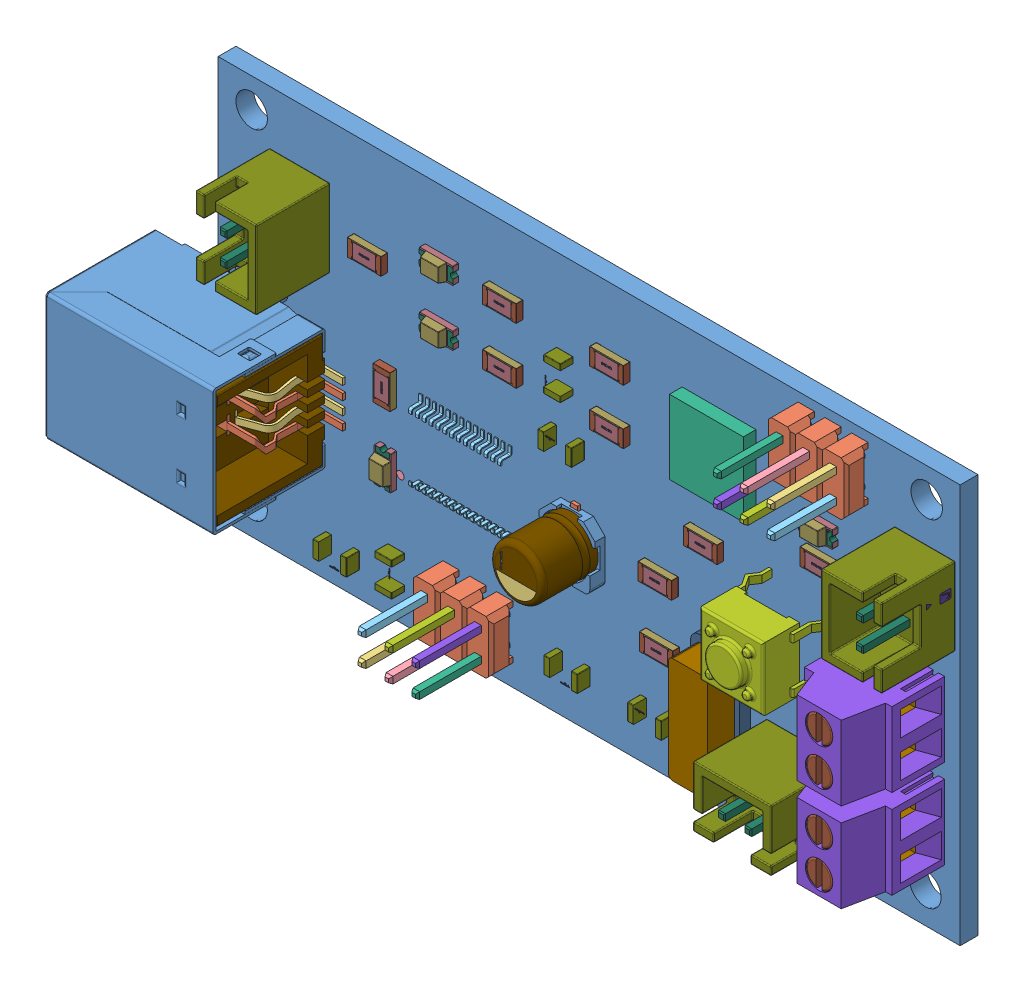
SolidWorks assembly MCU_PCB.step, configuration Default. Lengths in mm.
Overall size (75.68 37.85 14.81).
230 component instances, 41 part files, 0 mates.
Components (placement in the parent):
- Board.step-1: Board.step [Default] at origin size (70.36 37.85 1.69)
  - Open CASCADE STEP translator 7.5 1.1.1.step-1: Open CASCADE STEP translator 7.5 1.1.1.step [Default] at (0 0 -1.6914) size (70.36 37.85 1.69)
- J8.step-1: J8.step [Default] at origin size (7.62 5.08 11.68)
  - Conn_Harwin_M20-9980346_eec.step-1: Conn_Harwin_M20-9980346_eec.step [Default] at (78.623 59.827 2.54) x (1 0 0) z (0 -1 0) size (7.62 2.54 5.08)
  - Conn_Harwin_M20-9980346_eec-0.step-1: Conn_Harwin_M20-9980346_eec-0.step [Default] at (78.623 59.827 2.54) x (1 0 0) z (0 -1 0) size (0.64 11.68 0.63)
  - Conn_Harwin_M20-9980346_eec-1.step-1: Conn_Harwin_M20-9980346_eec-1.step [Default] at (78.623 59.827 2.54) x (1 0 0) z (0 -1 0) size (0.64 11.68 0.63)
  - Conn_Harwin_M20-9980346_eec-2.step-1: Conn_Harwin_M20-9980346_eec-2.step [Default] at (78.623 59.827 2.54) x (1 0 0) z (0 -1 0) size (0.64 11.68 0.63)
  - Conn_Harwin_M20-9980346_eec-3.step-1: Conn_Harwin_M20-9980346_eec-3.step [Default] at (78.623 59.827 2.54) x (1 0 0) z (0 -1 0) size (0.63 11.68 0.63)
  - Conn_Harwin_M20-9980346_eec-4.step-1: Conn_Harwin_M20-9980346_eec-4.step [Default] at (78.623 59.827 2.54) x (1 0 0) z (0 -1 0) size (0.64 11.68 0.63)
  - Conn_Harwin_M20-9980346_eec-5.step-1: Conn_Harwin_M20-9980346_eec-5.step [Default] at (78.623 59.827 2.54) x (1 0 0) z (0 -1 0) size (0.63 11.68 0.63)
- J7.step-1: J7.step [Default] at origin size (7.62 5.08 11.68)
  - Conn_Harwin_M20-9980346_eec.step-1: Conn_Harwin_M20-9980346_eec.step [Default] at (55.108 29.962 2.54) x (-1 0 0) z (0 1 0) size (7.62 2.54 5.08)
  - Conn_Harwin_M20-9980346_eec-0.step-1: Conn_Harwin_M20-9980346_eec-0.step [Default] at (55.108 29.962 2.54) x (-1 0 0) z (0 1 0) size (0.64 11.68 0.63)
  - Conn_Harwin_M20-9980346_eec-1.step-1: Conn_Harwin_M20-9980346_eec-1.step [Default] at (55.108 29.962 2.54) x (-1 0 0) z (0 1 0) size (0.64 11.68 0.63)
  - Conn_Harwin_M20-9980346_eec-2.step-1: Conn_Harwin_M20-9980346_eec-2.step [Default] at (55.108 29.962 2.54) x (-1 0 0) z (0 1 0) size (0.64 11.68 0.63)
  - Conn_Harwin_M20-9980346_eec-3.step-1: Conn_Harwin_M20-9980346_eec-3.step [Default] at (55.108 29.962 2.54) x (-1 0 0) z (0 1 0) size (0.63 11.68 0.63)
  - Conn_Harwin_M20-9980346_eec-4.step-1: Conn_Harwin_M20-9980346_eec-4.step [Default] at (55.108 29.962 2.54) x (-1 0 0) z (0 1 0) size (0.64 11.68 0.63)
  - Conn_Harwin_M20-9980346_eec-5.step-1: Conn_Harwin_M20-9980346_eec-5.step [Default] at (55.108 29.962 2.54) x (-1 0 0) z (0 1 0) size (0.63 11.68 0.63)
- Y1.step-1: Y1.step [Default] at origin size (4.66 11.36 3.61)
  - 6150083568.step-1: 6150083568.step [Default] at (73.5331 33.9361 1) size (3.71 10.05 2.61)
    - Extruded.step-1: Extruded.step [Default] at origin size (3.71 10.05 2.61)
  - 6150083488.step-1: 6150083488.step [Default] at (73.5329 33.9361 0) size (4.66 11.36 1.01)
    - Extruded-6.step-1: Extruded-6.step [Default] at origin size (4.66 11.36 1.01)
- R10.step-1: R10.step [Default] at origin size (3.2 1.6 0.65)
  - Res_Rohm_MCR18ERTFL1R10_eec.step-1: Res_Rohm_MCR18ERTFL1R10_eec.step [Default] at (39.8822 54.356 0) size (3.2 1.6 0.65)
  - Res_Rohm_MCR18ERTFL1R10_eec-7.step-1: Res_Rohm_MCR18ERTFL1R10_eec-7.step [Default] at (39.8822 54.356 0) size (3.15 1.6 0.6)
  - Res_Rohm_MCR18ERTFL1R10_eec-8.step-1: Res_Rohm_MCR18ERTFL1R10_eec-8.step [Default] at (39.8822 54.356 0) size (2.2 1.38 0.02)
  - Res_Rohm_MCR18ERTFL1R10_eec-9.step-1: Res_Rohm_MCR18ERTFL1R10_eec-9.step [Default] at (39.8822 54.356 0) size (0.94 0.2 0.01)
- J6.step-1: J6.step [Default] at origin size (5.75 7.4 10.4)
  - Conn_JST_B2B-XH-A_LF_SN_eec.step-1: Conn_JST_B2B-XH-A_LF_SN_eec.step [Default] at (33.147 54.483 0) x (0 1 0) z (0 0 1) size (7.4 5.75 10.4)
    - 1.step-1: 1.step [Default] at (0 0.025 0) x (-1 0 0) z (0 1 0) size (7.4 10.4 5.75)
      - 1-10.step-1: 1-10.step [Default] at origin size (3.14 10.2 0.64)
      - B2B-XH-A.step-1: B2B-XH-A.step [Default] at origin size (7.4 7 5.75)
      - JST Logo adjustable.step-1: JST Logo adjustable.step [Default] at (-1.7267 5.5034 2.841) size (0.85 2.3 0.01)
- J5.step-1: J5.step [Default] at origin size (17.39 16.2 11.97)
  - 62910416121.step-1: 62910416121.step [Default] at (28.2429 40.8111 5.85) x (0 -1 0) z (0 0 1) size (16.2 17.39 11.97)
    - 62910416121_Insulator_v2.step-1: 62910416121_Insulator_v2.step [Default] at origin size (11.54 15.82 11.72)
    - 62910416121_Shielding_v2.step-1: 62910416121_Shielding_v2.step [Default] at (0 -1.76 0) x (-1 0 0) z (0 1 0) size (16.2 11.15 16)
    - 62910416121_Pin_TOP.step-1: 62910416121_Pin_TOP.step [Default] at (-1.25 -7.258 1.225) x (0 1 0) z (0 0 1) size (16.49 2.05 8.16)
    - 62910416121_Pin_Bottom.step-1: 62910416121_Pin_Bottom.step [Default] at (-1.25 -7.258 -1.525) x (0 1 0) z (0 0 -1) size (16.47 1.78 5.44)
    - 62910416121_Pin_TOP.step-2: 62910416121_Pin_TOP.step [Default] at (1.245 -7.258 1.225) x (0 1 0) z (0 0 1) size (16.49 2.05 8.16)
    - 62910416121_Pin_Bottom.step-2: 62910416121_Pin_Bottom.step [Default] at (1.25 -7.258 -1.525) x (0 1 0) z (0 0 -1) size (16.47 1.78 5.44)
- U2.step-1: U2.step [Default] at origin size (14.3 7.8 1.91)
  - 6149939600.step-1: 6149939600.step [Default] at (48.895 41.275 0) x (0 1 0) z (0 0 1) size (7.8 14.3 1.91)
    - Body.step-1: Body.step [Default] at (-2.8 -5.25 0)
      - Open CASCADE STEP translator 6.8 6.2.1.x_t-1: Open CASCADE STEP translator 6.8 6.2.1.x_t [Default] at origin
    - Open CASCADE STEP translator 6.8 6.1.step-1: Open CASCADE STEP translator 6.8 6.1.step [Default] at (-2.8 -5.25 0.001) size (0.71 0.71 0.01)
    - Leader.step-1: Leader.step [Default] at (-2.8 -4.225 0) x (-1 0 0) z (0 0 1) size (1.1 0.3 1.07)
    - Leader.step-2: Leader.step [Default] at (-2.8 -3.575 0) x (-1 0 0) z (0 0 1) size (1.1 0.3 1.07)
    - Leader.step-3: Leader.step [Default] at (-2.8 -2.925 0) x (-1 0 0) z (0 0 1) size (1.1 0.3 1.07)
    - Leader.step-4: Leader.step [Default] at (-2.8 -2.275 0) x (-1 0 0) z (0 0 1) size (1.1 0.3 1.07)
    - Leader.step-5: Leader.step [Default] at (-2.8 -1.625 0) x (-1 0 0) z (0 0 1) size (1.1 0.3 1.07)
    - Leader.step-6: Leader.step [Default] at (-2.8 -0.975 0) x (-1 0 0) z (0 0 1) size (1.1 0.3 1.07)
    - Leader.step-7: Leader.step [Default] at (-2.8 -0.325 0) x (-1 0 0) z (0 0 1) size (1.1 0.3 1.07)
    - Leader.step-8: Leader.step [Default] at (-2.8 0.325 0) x (-1 0 0) z (0 0 1) size (1.1 0.3 1.07)
    - Leader.step-9: Leader.step [Default] at (-2.8 0.975 0) x (-1 0 0) z (0 0 1) size (1.1 0.3 1.07)
    - Leader.step-10: Leader.step [Default] at (-2.8 1.625 0) x (-1 0 0) z (0 0 1) size (1.1 0.3 1.07)
    - Leader.step-11: Leader.step [Default] at (-2.8 2.275 0) x (-1 0 0) z (0 0 1) size (1.1 0.3 1.07)
    - Leader.step-12: Leader.step [Default] at (-2.8 2.925 0) x (-1 0 0) z (0 0 1) size (1.1 0.3 1.07)
    - Leader.step-13: Leader.step [Default] at (-2.8 3.575 0) x (-1 0 0) z (0 0 1) size (1.1 0.3 1.07)
    - Leader.step-14: Leader.step [Default] at (-2.8 4.225 0) x (-1 0 0) z (0 0 1) size (1.1 0.3 1.07)
    - Leader.step-15: Leader.step [Default] at (2.8 -4.225 0) size (1.1 0.3 1.07)
    - Leader.step-16: Leader.step [Default] at (2.8 -3.575 0) size (1.1 0.3 1.07)
    - Leader.step-17: Leader.step [Default] at (2.8 -2.925 0) size (1.1 0.3 1.07)
    - Leader.step-18: Leader.step [Default] at (2.8 -2.275 0) size (1.1 0.3 1.07)
    - Leader.step-19: Leader.step [Default] at (2.8 -1.625 0) size (1.1 0.3 1.07)
    - Leader.step-20: Leader.step [Default] at (2.8 -0.975 0) size (1.1 0.3 1.07)
    - Leader.step-21: Leader.step [Default] at (2.8 -0.325 0) size (1.1 0.3 1.07)
    - Leader.step-22: Leader.step [Default] at (2.8 0.325 0) size (1.1 0.3 1.07)
    - Leader.step-23: Leader.step [Default] at (2.8 0.975 0) size (1.1 0.3 1.07)
    - Leader.step-24: Leader.step [Default] at (2.8 1.625 0) size (1.1 0.3 1.07)
    - Leader.step-25: Leader.step [Default] at (2.8 2.275 0) size (1.1 0.3 1.07)
    - Leader.step-26: Leader.step [Default] at (2.8 2.925 0) size (1.1 0.3 1.07)
    - Leader.step-27: Leader.step [Default] at (2.8 3.575 0) size (1.1 0.3 1.07)
    - Leader.step-28: Leader.step [Default] at (2.8 4.225 0) size (1.1 0.3 1.07)
- U1.step-1: U1.step [Default] at origin size (7 7 1.2)
  - 6204484576.step-1: 6204484576.step [Default] at (72.898 54.61 0) size (7 7 1.2)
    - Extruded-11.step-1: Extruded-11.step [Default] at origin size (7 7 1.2)
- SW1.step-1: SW1.step [Default] at origin size (7.9 6 7.79)
  - Switch_C&K_PTS645SM43SMTR92LFS_eec.step-1: Switch_C&K_PTS645SM43SMTR92LFS_eec.step [Default] at (81.026 44.831 0) x (-1 0 0) z (0 0 1) size (7.9 6 7.79)
- R9.step-1: R9.step [Default] at origin size (1.6 3.2 0.65)
  - Res_Rohm_MCR18ERTFL1R10_eec.step-1: Res_Rohm_MCR18ERTFL1R10_eec.step [Default] at (41.529 44.45 0) x (0 1 0) z (0 0 1) size (3.2 1.6 0.65)
  - Res_Rohm_MCR18ERTFL1R10_eec-7.step-1: Res_Rohm_MCR18ERTFL1R10_eec-7.step [Default] at (41.529 44.45 0) x (0 1 0) z (0 0 1) size (3.15 1.6 0.6)
  - Res_Rohm_MCR18ERTFL1R10_eec-8.step-1: Res_Rohm_MCR18ERTFL1R10_eec-8.step [Default] at (41.529 44.45 0) x (0 1 0) z (0 0 1) size (2.2 1.38 0.02)
  - Res_Rohm_MCR18ERTFL1R10_eec-9.step-1: Res_Rohm_MCR18ERTFL1R10_eec-9.step [Default] at (41.529 44.45 0) x (0 1 0) z (0 0 1) size (0.94 0.2 0.01)
- R8.step-1: R8.step [Default] at origin size (3.2 1.6 0.65)
  - Res_Rohm_MCR18ERTFL1R10_eec.step-1: Res_Rohm_MCR18ERTFL1R10_eec.step [Default] at (52.705 51.562 0) x (1 0 0) z (0 0 1) size (3.2 1.6 0.65)
  - Res_Rohm_MCR18ERTFL1R10_eec-7.step-1: Res_Rohm_MCR18ERTFL1R10_eec-7.step [Default] at (52.705 51.562 0) x (1 0 0) z (0 0 1) size (3.15 1.6 0.6)
  - Res_Rohm_MCR18ERTFL1R10_eec-8.step-1: Res_Rohm_MCR18ERTFL1R10_eec-8.step [Default] at (52.705 51.562 0) x (1 0 0) z (0 0 1) size (2.2 1.38 0.02)
  - Res_Rohm_MCR18ERTFL1R10_eec-9.step-1: Res_Rohm_MCR18ERTFL1R10_eec-9.step [Default] at (52.705 51.562 0) x (1 0 0) z (0 0 1) size (0.94 0.2 0.01)
- R7.step-1: R7.step [Default] at origin size (3.2 1.6 0.65)
  - Res_Rohm_MCR18ERTFL1R10_eec.step-1: Res_Rohm_MCR18ERTFL1R10_eec.step [Default] at (52.705 56.896 0) x (1 0 0) z (0 0 1) size (3.2 1.6 0.65)
  - Res_Rohm_MCR18ERTFL1R10_eec-7.step-1: Res_Rohm_MCR18ERTFL1R10_eec-7.step [Default] at (52.705 56.896 0) x (1 0 0) z (0 0 1) size (3.15 1.6 0.6)
  - Res_Rohm_MCR18ERTFL1R10_eec-8.step-1: Res_Rohm_MCR18ERTFL1R10_eec-8.step [Default] at (52.705 56.896 0) x (1 0 0) z (0 0 1) size (2.2 1.38 0.02)
  - Res_Rohm_MCR18ERTFL1R10_eec-9.step-1: Res_Rohm_MCR18ERTFL1R10_eec-9.step [Default] at (52.705 56.896 0) x (1 0 0) z (0 0 1) size (0.94 0.2 0.01)
- R6.step-1: R6.step [Default] at origin size (3.2 1.6 0.65)
  - Res_Rohm_MCR18ERTFL1R10_eec.step-1: Res_Rohm_MCR18ERTFL1R10_eec.step [Default] at (62.865 56.896 0) size (3.2 1.6 0.65)
  - Res_Rohm_MCR18ERTFL1R10_eec-7.step-1: Res_Rohm_MCR18ERTFL1R10_eec-7.step [Default] at (62.865 56.896 0) size (3.15 1.6 0.6)
  - Res_Rohm_MCR18ERTFL1R10_eec-8.step-1: Res_Rohm_MCR18ERTFL1R10_eec-8.step [Default] at (62.865 56.896 0) size (2.2 1.38 0.02)
  - Res_Rohm_MCR18ERTFL1R10_eec-9.step-1: Res_Rohm_MCR18ERTFL1R10_eec-9.step [Default] at (62.865 56.896 0) size (0.94 0.2 0.01)
- R5.step-1: R5.step [Default] at origin size (3.2 1.6 0.65)
  - Res_Rohm_MCR18ERTFL1R10_eec.step-1: Res_Rohm_MCR18ERTFL1R10_eec.step [Default] at (62.865 51.689 0) size (3.2 1.6 0.65)
  - Res_Rohm_MCR18ERTFL1R10_eec-7.step-1: Res_Rohm_MCR18ERTFL1R10_eec-7.step [Default] at (62.865 51.689 0) size (3.15 1.6 0.6)
  - Res_Rohm_MCR18ERTFL1R10_eec-8.step-1: Res_Rohm_MCR18ERTFL1R10_eec-8.step [Default] at (62.865 51.689 0) size (2.2 1.38 0.02)
  - Res_Rohm_MCR18ERTFL1R10_eec-9.step-1: Res_Rohm_MCR18ERTFL1R10_eec-9.step [Default] at (62.865 51.689 0) size (0.94 0.2 0.01)
- R4.step-1: R4.step [Default] at origin size (3.2 1.6 0.65)
  - Res_Rohm_MCR18ERTFL1R10_eec.step-1: Res_Rohm_MCR18ERTFL1R10_eec.step [Default] at (82.7998 50.419 0) size (3.2 1.6 0.65)
  - Res_Rohm_MCR18ERTFL1R10_eec-7.step-1: Res_Rohm_MCR18ERTFL1R10_eec-7.step [Default] at (82.7998 50.419 0) size (3.15 1.6 0.6)
  - Res_Rohm_MCR18ERTFL1R10_eec-8.step-1: Res_Rohm_MCR18ERTFL1R10_eec-8.step [Default] at (82.7998 50.419 0) size (2.2 1.38 0.02)
  - Res_Rohm_MCR18ERTFL1R10_eec-9.step-1: Res_Rohm_MCR18ERTFL1R10_eec-9.step [Default] at (82.7998 50.419 0) size (0.94 0.2 0.01)
- R3.step-1: R3.step [Default] at origin size (3.2 1.6 0.65)
  - Res_Rohm_MCR18ERTFL1R10_eec.step-1: Res_Rohm_MCR18ERTFL1R10_eec.step [Default] at (67.4412 41.529 0) x (1 0 0) z (0 0 1) size (3.2 1.6 0.65)
  - Res_Rohm_MCR18ERTFL1R10_eec-7.step-1: Res_Rohm_MCR18ERTFL1R10_eec-7.step [Default] at (67.4412 41.529 0) x (1 0 0) z (0 0 1) size (3.15 1.6 0.6)
  - Res_Rohm_MCR18ERTFL1R10_eec-8.step-1: Res_Rohm_MCR18ERTFL1R10_eec-8.step [Default] at (67.4412 41.529 0) x (1 0 0) z (0 0 1) size (2.2 1.38 0.02)
  - Res_Rohm_MCR18ERTFL1R10_eec-9.step-1: Res_Rohm_MCR18ERTFL1R10_eec-9.step [Default] at (67.4412 41.529 0) x (1 0 0) z (0 0 1) size (0.94 0.2 0.01)
- R2.step-1: R2.step [Default] at origin size (3.2 1.6 0.65)
  - Res_Rohm_MCR18ERTFL1R10_eec.step-1: Res_Rohm_MCR18ERTFL1R10_eec.step [Default] at (71.755 46.609 0) x (1 0 0) z (0 0 1) size (3.2 1.6 0.65)
  - Res_Rohm_MCR18ERTFL1R10_eec-7.step-1: Res_Rohm_MCR18ERTFL1R10_eec-7.step [Default] at (71.755 46.609 0) x (1 0 0) z (0 0 1) size (3.15 1.6 0.6)
  - Res_Rohm_MCR18ERTFL1R10_eec-8.step-1: Res_Rohm_MCR18ERTFL1R10_eec-8.step [Default] at (71.755 46.609 0) x (1 0 0) z (0 0 1) size (2.2 1.38 0.02)
  - Res_Rohm_MCR18ERTFL1R10_eec-9.step-1: Res_Rohm_MCR18ERTFL1R10_eec-9.step [Default] at (71.755 46.609 0) x (1 0 0) z (0 0 1) size (0.94 0.2 0.01)
- R1.step-1: R1.step [Default] at origin size (3.2 1.6 0.65)
  - Res_Rohm_MCR18ERTFL1R10_eec.step-1: Res_Rohm_MCR18ERTFL1R10_eec.step [Default] at (67.564 35.814 0) x (1 0 0) z (0 0 1) size (3.2 1.6 0.65)
  - Res_Rohm_MCR18ERTFL1R10_eec-7.step-1: Res_Rohm_MCR18ERTFL1R10_eec-7.step [Default] at (67.564 35.814 0) x (1 0 0) z (0 0 1) size (3.15 1.6 0.6)
  - Res_Rohm_MCR18ERTFL1R10_eec-8.step-1: Res_Rohm_MCR18ERTFL1R10_eec-8.step [Default] at (67.564 35.814 0) x (1 0 0) z (0 0 1) size (2.2 1.38 0.02)
  - Res_Rohm_MCR18ERTFL1R10_eec-9.step-1: Res_Rohm_MCR18ERTFL1R10_eec-9.step [Default] at (67.564 35.814 0) x (1 0 0) z (0 0 1) size (0.94 0.2 0.01)
- J4.step-1: J4.step [Default] at origin size (7.4 5.75 10.4)
  - Conn_JST_B2B-XH-A_LF_SN_eec.step-1: Conn_JST_B2B-XH-A_LF_SN_eec.step [Default] at (81.133 32.021 0) x (-1 0 0) z (0 0 1) size (7.4 5.75 10.4)
    - 1.step-1: 1.step [Default] at (0 0.025 0) x (-1 0 0) z (0 1 0) size (7.4 10.4 5.75)
      - 1-10.step-1: 1-10.step [Default] at origin size (3.14 10.2 0.64)
      - B2B-XH-A.step-1: B2B-XH-A.step [Default] at origin size (7.4 7 5.75)
      - JST Logo adjustable.step-1: JST Logo adjustable.step [Default] at (-1.7267 5.5034 2.841) size (0.85 2.3 0.01)
- J3.step-1: J3.step [Default] at origin size (5.75 7.4 10.4)
  - Conn_JST_B2B-XH-A_LF_SN_eec.step-1: Conn_JST_B2B-XH-A_LF_SN_eec.step [Default] at (92.439 53.066 0) x (0 -1 0) z (0 0 1) size (7.4 5.75 10.4)
    - 1.step-1: 1.step [Default] at (0 0.025 0) x (-1 0 0) z (0 1 0) size (7.4 10.4 5.75)
      - 1-10.step-1: 1-10.step [Default] at origin size (3.14 10.2 0.64)
      - B2B-XH-A.step-1: B2B-XH-A.step [Default] at origin size (7.4 7 5.75)
      - JST Logo adjustable.step-1: JST Logo adjustable.step [Default] at (-1.7267 5.5034 2.841) size (0.85 2.3 0.01)
- J2.step-1: J2.step [Default] at origin size (7.4 7.45 12.2)
  - 691214110002.step-1: 691214110002.step [Default] at (90.632 34.8719 3) x (0 1 0) z (0 0 1) size (7.45 7.4 12.2)
    - 691214110002-12.step-1: 691214110002-12.step [Default] at origin size (7.45 7.4 8.5)
    - 6912141100xx_CAGE.step-1: 6912141100xx_CAGE.step [Default] at (1.725 -0.3 -0.125) size (2.6 3.95 4.15)
    - 6912141100xx_CAGE.step-2: 6912141100xx_CAGE.step [Default] at (-1.775 -0.3 -0.125) size (2.6 3.95 4.15)
    - 6912141100xx_PIN.step-1: 6912141100xx_PIN.step [Default] at (1.775 0.145 -1.2) x (1 0 0) z (0 1 0) size (2 7.15 4.8)
    - 6912141100xx_PIN.step-2: 6912141100xx_PIN.step [Default] at (-1.725 0.145 -1.2) x (1 0 0) z (0 1 0) size (2 7.15 4.8)
    - 6912141100xx_VIS.step-1: 6912141100xx_VIS.step [Default] at (1.725 -0.3 4.45) size (2.6 2.6 4.2)
    - 6912141100xx_VIS.step-2: 6912141100xx_VIS.step [Default] at (-1.775 -0.3 4.45) size (2.6 2.6 4.2)
- J1.step-1: J1.step [Default] at origin size (7.4 7.45 12.2)
  - 691214110002.step-1: 691214110002.step [Default] at (90.632 43.3099 3) x (0 1 0) z (0 0 1) size (7.45 7.4 12.2)
    - 691214110002-12.step-1: 691214110002-12.step [Default] at origin size (7.45 7.4 8.5)
    - 6912141100xx_CAGE.step-1: 6912141100xx_CAGE.step [Default] at (1.725 -0.3 -0.125) size (2.6 3.95 4.15)
    - 6912141100xx_CAGE.step-2: 6912141100xx_CAGE.step [Default] at (-1.775 -0.3 -0.125) size (2.6 3.95 4.15)
    - 6912141100xx_PIN.step-1: 6912141100xx_PIN.step [Default] at (1.775 0.145 -1.2) x (1 0 0) z (0 1 0) size (2 7.15 4.8)
    - 6912141100xx_PIN.step-2: 6912141100xx_PIN.step [Default] at (-1.725 0.145 -1.2) x (1 0 0) z (0 1 0) size (2 7.15 4.8)
    - 6912141100xx_VIS.step-1: 6912141100xx_VIS.step [Default] at (1.725 -0.3 4.45) size (2.6 2.6 4.2)
    - 6912141100xx_VIS.step-2: 6912141100xx_VIS.step [Default] at (-1.775 -0.3 4.45) size (2.6 2.6 4.2)
- D4.step-1: D4.step [Default] at origin size (1.6 3.2 1.2)
  - Diode_Broadcom_HSMG-C150_eec.step-1: Diode_Broadcom_HSMG-C150_eec.step [Default] at (41.529 37.719 0) x (0 1 0) z (0 0 1) size (3.2 1.6 1.2)
    - 1-13.step-1: 1-13.step [Default] at origin size (2 1.6 0.66)
    - 2.step-1: 2.step [Default] at origin size (3.2 1.6 0.53)
    - 3.step-1: 3.step [Default] at origin size (0.35 1.6 0.01)
    - 4.step-1: 4.step [Default] at origin size (3.2 1.3 0.55)
- D3.step-1: D3.step [Default] at origin size (3.2 1.6 1.2)
  - Diode_Broadcom_HSMG-C150_eec.step-1: Diode_Broadcom_HSMG-C150_eec.step [Default] at (46.609 51.562 0) x (1 0 0) z (0 0 1) size (3.2 1.6 1.2)
    - 1-13.step-1: 1-13.step [Default] at origin size (2 1.6 0.66)
    - 2.step-1: 2.step [Default] at origin size (3.2 1.6 0.53)
    - 3.step-1: 3.step [Default] at origin size (0.35 1.6 0.01)
    - 4.step-1: 4.step [Default] at origin size (3.2 1.3 0.55)
- D2.step-1: D2.step [Default] at origin size (3.2 1.6 1.2)
  - Diode_Broadcom_HSMG-C150_eec.step-1: Diode_Broadcom_HSMG-C150_eec.step [Default] at (46.609 56.896 0) x (1 0 0) z (0 0 1) size (3.2 1.6 1.2)
    - 1-13.step-1: 1-13.step [Default] at origin size (2 1.6 0.66)
    - 2.step-1: 2.step [Default] at origin size (3.2 1.6 0.53)
    - 3.step-1: 3.step [Default] at origin size (0.35 1.6 0.01)
    - 4.step-1: 4.step [Default] at origin size (3.2 1.3 0.55)
- D1.step-1: D1.step [Default] at origin size (3.2 1.6 1.2)
  - Diode_Broadcom_HSMG-C150_eec.step-1: Diode_Broadcom_HSMG-C150_eec.step [Default] at (82.578 53.213 0) x (-1 0 0) z (0 0 1) size (3.2 1.6 1.2)
    - 1-13.step-1: 1-13.step [Default] at origin size (2 1.6 0.66)
    - 2.step-1: 2.step [Default] at origin size (3.2 1.6 0.53)
    - 3.step-1: 3.step [Default] at origin size (0.35 1.6 0.01)
    - 4.step-1: 4.step [Default] at origin size (3.2 1.3 0.55)
- C7.step-1: C7.step [Default] at origin size (3.2 1.6 1.26)
  - Cap_Murata_GRM31M3U1H683JA01K_eec.step-1: Cap_Murata_GRM31M3U1H683JA01K_eec.step [Default] at (58.547 48.26 0) x (-1 0 0) z (0 0 1) size (3.2 1.6 1.26)
    - Body.step-1: Body.step [Default] x (-1 0 0) z (0 0 1)
      - Open CASCADE STEP translator 6.8 6.2.1.x_t-1: Open CASCADE STEP translator 6.8 6.2.1.x_t [Default] at origin
    - side.step-1: side.step [Default] at (-1.3 0.0917 0) x (-1 0 0) z (0 0 1) size (0.55 1.6 1.25)
    - side.step-2: side.step [Default] at (1.3 0.0917 1.25) x (1 0 0) z (0 0 -1) size (0.55 1.6 1.25)
    - Murata.step-1: Murata.step [Default] at (-0.5 -1.0194 1.2465) size (0.91 0.21 0.01)
- C6.step-1: C6.step [Default] at origin size (3.2 1.6 1.26)
  - Cap_Murata_GRM31M3U1H683JA01K_eec.step-1: Cap_Murata_GRM31M3U1H683JA01K_eec.step [Default] at (37.211 28.575 0) x (1 0 0) z (0 0 1) size (3.2 1.6 1.26)
    - Body.step-1: Body.step [Default] x (-1 0 0) z (0 0 1)
      - Open CASCADE STEP translator 6.8 6.2.1.x_t-1: Open CASCADE STEP translator 6.8 6.2.1.x_t [Default] at origin
    - side.step-1: side.step [Default] at (-1.3 0.0917 0) x (-1 0 0) z (0 0 1) size (0.55 1.6 1.25)
    - side.step-2: side.step [Default] at (1.3 0.0917 1.25) x (1 0 0) z (0 0 -1) size (0.55 1.6 1.25)
    - Murata.step-1: Murata.step [Default] at (-0.5 -1.0194 1.2465) size (0.91 0.21 0.01)
- C5.step-1: C5.step [Default] at origin size (5.3 6 5.82)
  - Cap_Panasonic_Electronic_Components_EEE-1AA101WR_eec.step-1: Cap_Panasonic_Electronic_Components_EEE-1AA101WR_eec.step [Default] at (59.436 40.64 0) x (0 1 0) z (0 0 1) size (6 5.3 5.82)
    - _____5 SIZE CODE C.step-1: _____5 SIZE CODE C.step [Default] x (1 0 0) z (0 -1 0) size (6 5.82 5.3)
      - ___W_____SIZE CODE C-001.step-1: ___W_____SIZE CODE C-001.step [Default] at (0 0.5 0) size (5 5.3 5)
      - ___W_____SIZE CODE C-002.step-1: ___W_____SIZE CODE C-002.step [Default] at origin size (5.3 1.45 5.3)
      - ___W_____SIZE CODE C-003.step-1: ___W_____SIZE CODE C-003.step [Default] at (-0.75 0.3 0) size (2.58 1 0.65)
      - ___W_____SIZE CODE C-003.step-2: ___W_____SIZE CODE C-003.step [Default] at (0.75 0.3 0) x (-1 0 0) z (0 0 -1) size (2.58 1 0.65)
      - 1-14.step-1: 1-14.step [Default] at (0 0.499 0) size (1.49 0.2 3.86)
      - Panasonic Logo.step-1: Panasonic Logo.step [Default] at (-0.9594 5.701 -1.5139) x (1 0 0) z (0 1 0) size (1.5 0.24 0.15)
- C4.step-1: C4.step [Default] at origin size (3.2 1.6 1.26)
  - Cap_Murata_GRM31M3U1H683JA01K_eec.step-1: Cap_Murata_GRM31M3U1H683JA01K_eec.step [Default] at (67.056 30.099 0) x (-1 0 0) z (0 0 1) size (3.2 1.6 1.26)
    - Body.step-1: Body.step [Default] x (-1 0 0) z (0 0 1)
      - Open CASCADE STEP translator 6.8 6.2.1.x_t-1: Open CASCADE STEP translator 6.8 6.2.1.x_t [Default] at origin
    - side.step-1: side.step [Default] at (-1.3 0.0917 0) x (-1 0 0) z (0 0 1) size (0.55 1.6 1.25)
    - side.step-2: side.step [Default] at (1.3 0.0917 1.25) x (1 0 0) z (0 0 -1) size (0.55 1.6 1.25)
    - Murata.step-1: Murata.step [Default] at (-0.5 -1.0194 1.2465) size (0.91 0.21 0.01)
- C3.step-1: C3.step [Default] at origin size (3.2 1.6 1.26)
  - Cap_Murata_GRM31M3U1H683JA01K_eec.step-1: Cap_Murata_GRM31M3U1H683JA01K_eec.step [Default] at (59.1028 29.972 0) x (1 0 0) z (0 0 1) size (3.2 1.6 1.26)
    - Body.step-1: Body.step [Default] x (-1 0 0) z (0 0 1)
      - Open CASCADE STEP translator 6.8 6.2.1.x_t-1: Open CASCADE STEP translator 6.8 6.2.1.x_t [Default] at origin
    - side.step-1: side.step [Default] at (-1.3 0.0917 0) x (-1 0 0) z (0 0 1) size (0.55 1.6 1.25)
    - side.step-2: side.step [Default] at (1.3 0.0917 1.25) x (1 0 0) z (0 0 -1) size (0.55 1.6 1.25)
    - Murata.step-1: Murata.step [Default] at (-0.5 -1.0194 1.2465) size (0.91 0.21 0.01)
- C2.step-1: C2.step [Default] at origin size (1.6 3.2 1.26)
  - Cap_Murata_GRM31M3U1H683JA01K_eec.step-1: Cap_Murata_GRM31M3U1H683JA01K_eec.step [Default] at (58.293 53.848 0) x (0 -1 0) z (0 0 1) size (3.2 1.6 1.26)
    - Body.step-1: Body.step [Default] x (-1 0 0) z (0 0 1)
      - Open CASCADE STEP translator 6.8 6.2.1.x_t-1: Open CASCADE STEP translator 6.8 6.2.1.x_t [Default] at origin
    - side.step-1: side.step [Default] at (-1.3 0.0917 0) x (-1 0 0) z (0 0 1) size (0.55 1.6 1.25)
    - side.step-2: side.step [Default] at (1.3 0.0917 1.25) x (1 0 0) z (0 0 -1) size (0.55 1.6 1.25)
    - Murata.step-1: Murata.step [Default] at (-0.5 -1.0194 1.2465) size (0.91 0.21 0.01)
- C1.step-1: C1.step [Default] at origin size (1.6 3.2 1.26)
  - Cap_Murata_GRM31M3U1H683JA01K_eec.step-1: Cap_Murata_GRM31M3U1H683JA01K_eec.step [Default] at (42.291 29.718 0) x (0 1 0) z (0 0 1) size (3.2 1.6 1.26)
    - Body.step-1: Body.step [Default] x (-1 0 0) z (0 0 1)
      - Open CASCADE STEP translator 6.8 6.2.1.x_t-1: Open CASCADE STEP translator 6.8 6.2.1.x_t [Default] at origin
    - side.step-1: side.step [Default] at (-1.3 0.0917 0) x (-1 0 0) z (0 0 1) size (0.55 1.6 1.25)
    - side.step-2: side.step [Default] at (1.3 0.0917 1.25) x (1 0 0) z (0 0 -1) size (0.55 1.6 1.25)
    - Murata.step-1: Murata.step [Default] at (-0.5 -1.0194 1.2465) size (0.91 0.21 0.01)
